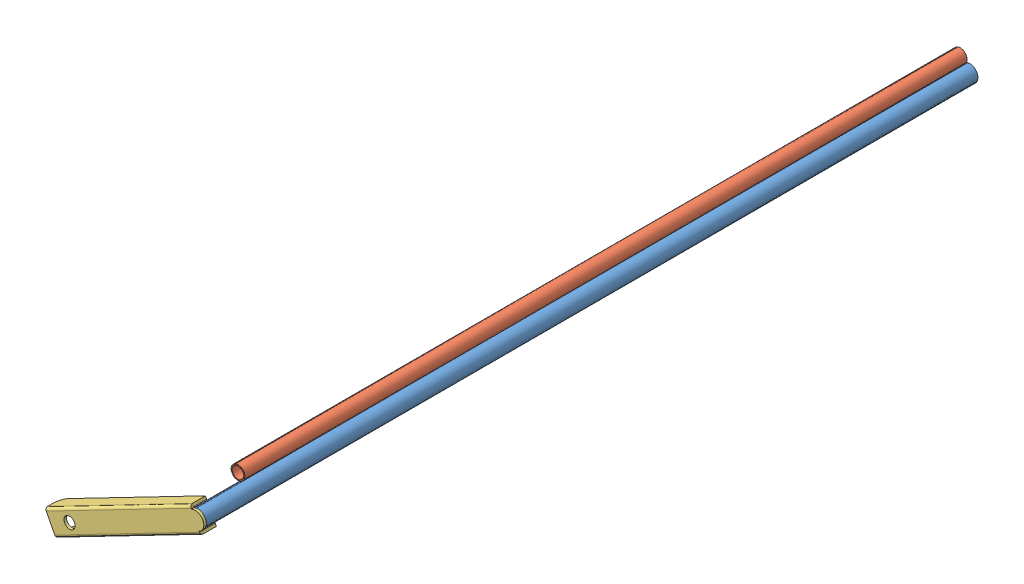
SolidWorks assembly 軌道凸輪把手-1, configuration 預設. Lengths in mm.
Overall size (190.33 126.2 903).
3 component instances, 3 part files, 4 mates.
Components (placement in the parent):
- LB-A54-12-13-1: LB-A54-12-13 [預設] at (-5740.9326 -6068.5718 -450) size (19.02 19.02 900)
- LB-A54-12-14-1: LB-A54-12-14 [預設] at (-140383.7891 55739.1161 -446) x (0.903117 -0.429395 0) z (0 0 1) size (16 16 842)
- LB-A54-12-10-1: LB-A54-12-10 [預設] at (-15.1122 -11.8736 453) x (-0.888161 -0.459533 0) z (0 0 -1) size (200 27.64 18.32)
Mates (geometry in assembly coordinates):
- 相切1: tangent anti-aligned: cylinder of LB-A54-12-13-1 through (-36.2633 7.245 450) axis (0 0 -1) radius 9.51; cylinder of LB-A54-12-14-1 through (-43.475 23.2009 396) axis (0 0 -1) radius 8
- 平行相距3: distance = 4 mm aligned: plane of LB-A54-12-13-1 through (-36.2633 7.245 -450) normal (0 0 -1); plane of LB-A54-12-14-1 through (-43.475 23.2009 -446) normal (0 0 -1)
- 重合/共線/共點5: coincident anti-aligned: plane of LB-A54-12-13-1 through (-36.2633 7.245 450) normal (0 0 1); plane of LB-A54-12-10-1 through (-36.2633 7.245 450) normal (0 0 -1)
- 同軸心2: concentric anti-aligned: cylinder of LB-A54-12-13-1 through (-36.2633 7.245 450) axis (0 0 -1) radius 9.51; cylinder of LB-A54-12-10-1 through (-36.2633 7.245 450) axis (0 0 1) radius 10
